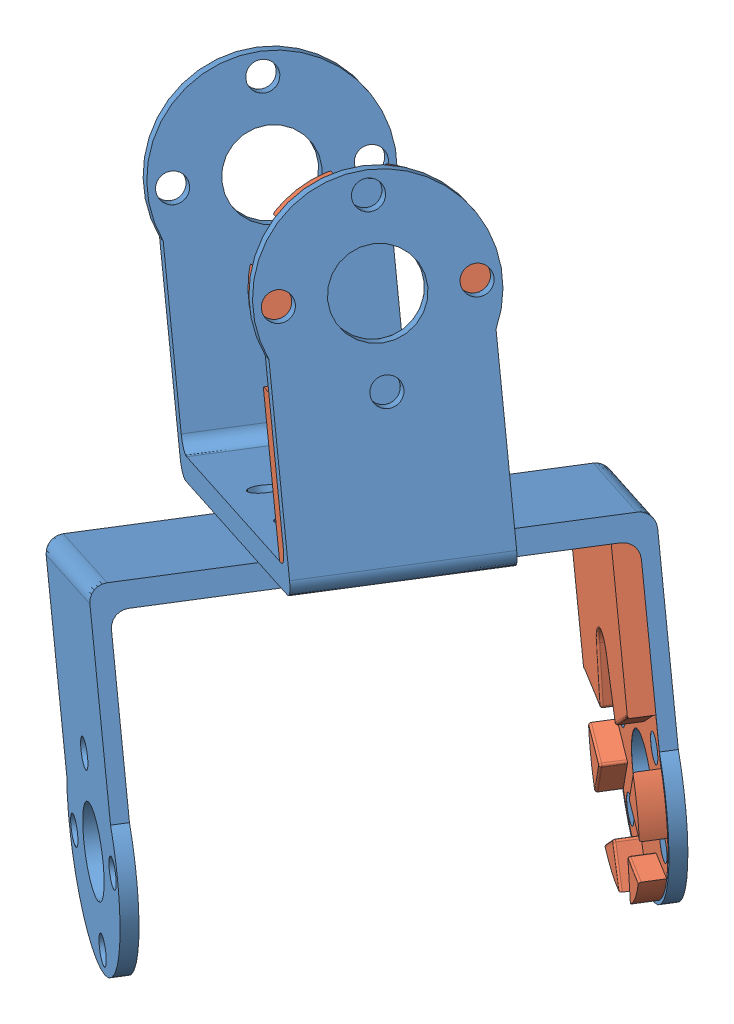
SolidWorks assembly box3_90_left_supplement, configuration Predeterminado. Lengths in mm.
Overall size (85.69 98.73 75.62).
4 component instances, 2 part files, 8 mates.
Components (placement in the parent):
- u_bracket-1: u_bracket [Predeterminado] at (132.1357 -74.2778 -18.2854) x (0.773259 0.381087 0.506798) z (-0.543971 -0.012024 0.839018) size (60 44.22 26.36)
- u_bracket-2: u_bracket [Predeterminado] at (132.7874 -76.1267 -17.8894) x (-0.543971 -0.012024 0.839018) z (0.773259 0.381087 0.506798) size (60 44.22 26.36)
- supplement_u_f_horn-2: supplement_u_f_horn [Predeterminado] at (157.8066 -103.5608 -35.4339) x (0.325832 -0.924461 0.198002) z (-0.773259 -0.381087 -0.506798) size (40.74 3.02 25.4)
- supplement_u_f_horn-3: supplement_u_f_horn [Predeterminado] at (143.999 -35.8365 -10.043) x (-0.325832 0.924461 -0.198002) z (-0.543971 -0.012024 0.839018) size (40.74 3.02 25.4)
Mates (geometry in assembly coordinates):
- Coincidente16: coincident anti-aligned: plane of u_bracket-1 through (132.4616 -75.2022 -18.0874) normal (0.325832 -0.924461 0.198002); plane of u_bracket-2 through (132.4616 -75.2022 -18.0874) normal (-0.325832 0.924461 -0.198002)
- Concéntrica55: concentric anti-aligned: cylinder of u_bracket-1 through (118.0529 -34.3216 -26.8432) axis (0.325832 -0.924461 0.198002) radius 5.4; cylinder of u_bracket-2 through (146.8702 -116.0828 -9.3315) axis (-0.325832 0.924461 -0.198002) radius 5.4
- Paralelo2: parallel aligned: plane of u_bracket-1 through (101.7587 -84.0057 -23.8171) normal (-0.543971 -0.012024 0.839018); plane of u_bracket-2 through (107.8408 -82.9094 1.5956) normal (-0.543971 -0.012024 0.839018)
- Coincidente18: coincident anti-aligned: cylinder of u_bracket-2 through (157.8066 -103.5608 -35.4339) axis (0.543971 0.012024 -0.839018) radius 5.3; circle of supplement_u_f_horn-2
- Coincidente19: coincident anti-aligned: plane of u_bracket-2 through (157.8066 -103.5608 -35.4339) normal (-0.543971 -0.012024 0.839018); plane of supplement_u_f_horn-2 through (157.8066 -103.5608 -35.4339) normal (0.543971 0.012024 -0.839018)
- Coincidente20: coincident aligned: plane of u_bracket-2 through (140.4791 -82.1879 -48.7455) normal (-0.773259 -0.381087 -0.506798); plane of supplement_u_f_horn-2 through (137.7592 -82.2481 -44.5504) normal (-0.773259 -0.381087 -0.506798)
- Coincidente21: coincident anti-aligned: circle of u_bracket-1; circle of supplement_u_f_horn-3
- Coincidente22: coincident aligned: plane of u_bracket-1 through (101.7587 -84.0057 -23.8171) normal (-0.543971 -0.012024 0.839018); plane of supplement_u_f_horn-3 through (144.2879 -63.046 4.0568) normal (-0.543971 -0.012024 0.839018)
